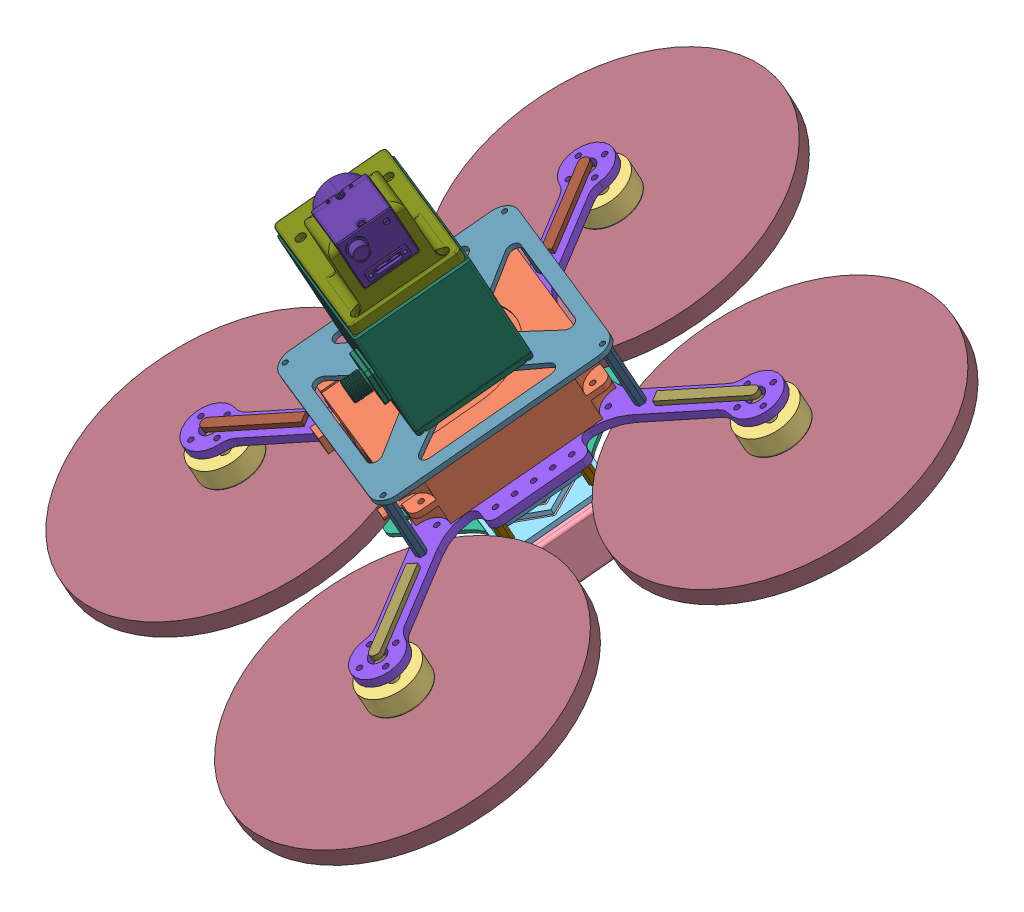
SolidWorks assembly yunque-M, configuration 默认. Lengths in mm.
Overall size (433.72 298.75 419.83).
35 component instances, 18 part files, 70 mates.
Components (placement in the parent):
- CUAV Nora飞控-1: CUAV Nora飞控 [默认] at (-183.0689 -174.3038 102.8039) x (0.916661 0.047717 0.396806) z (-0.335209 -0.448868 0.828343) size (64 22 46)
- intel_nuc-1: intel_nuc [默认] at (-190.8807 -143.3153 117.086) x (-0.335209 -0.448868 0.828343) z (-0.21764 0.892323 0.395465) size (117 105 32)
- T-motor F90电机-1: T-motor F90电机 [默认] at (-132.2317 -187.4888 236.3923) x (-0.916661 -0.047717 -0.396806) z (-0.335209 -0.448868 0.828343) size (34.07 34.7 34.07)
- 电池-1: 电池 [默认] at (-177.2712 -190.2979 96.5676) x (-0.916661 -0.047717 -0.396806) z (-0.335209 -0.448868 0.828343) size (108.03 30.1 54)
- 电池固定板-1: 电池固定板 [默认] at (-183.2633 -174.5466 103.2447) x (-0.916661 -0.047717 -0.396806) z (-0.335209 -0.448868 0.828343) size (95 3 56)
- 电池着陆板-1: 电池着陆板 [默认] at (-180.5748 -203.9008 87.5127) x (-0.916661 -0.047717 -0.396806) z (-0.335209 -0.448868 0.828343) size (125 2 125)
- 飞控垫板-1: 飞控垫板 [默认] at (-188.7043 -152.2385 113.1314) x (0.916661 0.047717 0.396806) z (-0.335209 -0.448868 0.828343) size (40 5 40)
- 主机架碳板-1: 主机架碳板 [默认] at (-189.7925 -147.7769 115.1087) x (0.916661 0.047717 0.396806) z (-0.335209 -0.448868 0.828343) size (225.99 5 225.99)
- T-motor F90电机-2: T-motor F90电机 [默认] at (-313.7213 -196.9363 157.8287) x (-0.916661 -0.047717 -0.396806) z (-0.335209 -0.448868 0.828343) size (34.07 34.7 34.07)
- T-motor F90电机-3: T-motor F90电机 [默认] at (-65.8637 -98.6175 72.3887) x (-0.335209 -0.448868 0.828343) z (0.916661 0.047717 0.396806) size (34.07 34.7 34.07)
- T-motor F90电机-4: T-motor F90电机 [默认] at (-247.3534 -108.065 -6.1749) x (-0.916661 -0.047717 -0.396806) z (-0.335209 -0.448868 0.828343) size (34.07 34.7 34.07)
- 30mm铜柱-1: 30mm铜柱 [默认] at (-153.6807 -182.7136 137.9531) x (0.973897 0.225307 0.027593) z (0.064479 -0.391147 0.918066) size (5.77 30 5.05)
- 30mm铜柱-2: 30mm铜柱 [默认] at (-138.5963 -162.5145 100.6777) x (0.973897 0.225307 0.027593) z (0.064479 -0.391147 0.918066) size (5.77 30 5.05)
- 30mm铜柱-3: 30mm铜柱 [默认] at (-212.8459 -166.3796 68.5364) x (0.973897 0.225307 0.027593) z (0.064479 -0.391147 0.918066) size (5.77 30 5.05)
- 30mm铜柱-4: 30mm铜柱 [默认] at (-227.9303 -186.5787 105.8118) x (0.973897 0.225307 0.027593) z (0.064479 -0.391147 0.918066) size (5.77 30 5.05)
- 35mm铜柱 -1: 35mm铜柱  [默认] at (-224.3142 -120.2491 46.6399) x (0.973875 0.225437 0.027287) z (0.064804 -0.391072 0.918076) size (5.77 35 5.05)
- 35mm铜柱 -2: 35mm铜柱  [默认] at (-262.8632 -171.8689 141.8994) x (0.973897 0.225307 0.027593) z (0.064479 -0.391147 0.918066) size (5.77 35 5.05)
- 35mm铜柱 -3: 35mm铜柱  [默认] at (-118.8982 -114.7616 92.2727) x (0.973897 0.225307 0.027593) z (0.064479 -0.391147 0.918066) size (5.77 35 5.05)
- 35mm铜柱 -4: 35mm铜柱  [默认] at (-157.4472 -166.3815 187.5321) x (0.973897 0.225307 0.027593) z (0.064479 -0.391147 0.918066) size (5.77 35 5.05)
- 灯板-1: 灯板 [默认] at (-315.4624 -189.7978 160.9924) x (0.885206 0.351139 -0.305143) z (-0.411149 0.283657 -0.866311) size (53 3 6)
- 灯板-B-1: 灯板-B [默认] at (-133.9728 -180.3503 239.556) x (-0.411149 0.283657 -0.866311) z (-0.885206 -0.351139 0.305143) size (53 3 6)
- 灯板-2: 灯板 [默认] at (-248.4416 -103.6033 -4.1976) x (0.411149 -0.283657 0.866311) z (-0.885206 -0.351139 0.305143) size (53 3 6)
- 灯板-B-2: 灯板-B [默认] at (-67.6048 -91.4789 75.5524) x (-0.885206 -0.351139 0.305143) z (0.411149 -0.283657 0.866311) size (53 3 6)
- full_blade-1: full_blade [默认] at (-59.3998 -125.1195 60.6434) x (0.974969 0.21764 0.045483) z (0.045483 -0.395465 0.917354) size (180 10 180)
- full_blade-2: full_blade [默认] at (-125.7678 -213.9908 224.647) x (0.974969 0.21764 0.045483) z (0.045483 -0.395465 0.917354) size (180 10 180)
- full_blade-3: full_blade [默认] at (-240.8895 -134.5669 -17.9202) x (0.974969 0.21764 0.045483) z (0.045483 -0.395465 0.917354) size (180 10 180)
- full_blade-5: full_blade [默认] at (-307.2574 -223.4383 146.0834) x (0.974969 0.21764 0.045483) z (0.045483 -0.395465 0.917354) size (180 10 180)
- flying_LIVO-1: flying_LIVO [默认] at (-159.7602 -217.8236 77.0282) x (0.916661 0.047717 0.396806) z (-0.21764 0.892323 0.395465) size (125.6 125.3 113.3)
  - fly_base-1: fly_base [默认] at (-71.8765 52.4809 124.1) size (125.6 125.3 3)
  - AVIA-1: AVIA [Default] at (-81.3765 -48.6691 111.2) x (1 0 0) z (0 -1 0) size (91.02 64.8 76.07)
    - Livox_Avia_shell_FOV.stp-1: Livox_Avia_shell_FOV.stp [Default] at origin size (1207.64 1420.81 1420.81)
      - LIVOX_AVIA.stp-1: LIVOX_AVIA.stp [Default] at origin size (91.02 64.8 76.07)
      - LIVOX_AVIA_FOV.stp-1: LIVOX_AVIA_FOV.stp [Default] at (19.97 48.3 -38.5) x (0 0 -1) z (1 0 0) size (1420.81 1420.81 1123.13) (hidden)
  - T_cam_livox-1: T_cam_livox [默认] at (-9.0765 -10.1691 198.4) x (0 1 0) z (0 0 -1) size (59.2 89 45.5)
  - FL2-020-R0-1: FL2-020-R0 [Default] at (9.3053 -10.1691 222.9) x (0 -1 0) z (-1 0 0) size (29 29 47.76)
Mates (geometry in assembly coordinates):
- 重合1: coincident anti-aligned: plane of 主机架碳板-1 through (-247.3534 -108.065 -6.1749) normal (0.21764 -0.892323 -0.395465); plane of T-motor F90电机-4 through (-242.9992 -107.8383 -4.2901) normal (-0.21764 0.892323 0.395465)
- 同心3: concentric anti-aligned: circle of 主机架碳板-1; circle of T-motor F90电机-4
- 同心4: concentric anti-aligned: circle of 主机架碳板-1; circle of T-motor F90电机-4
- 重合2: coincident anti-aligned: plane of 主机架碳板-1 through (-247.3534 -108.065 -6.1749) normal (0.21764 -0.892323 -0.395465); plane of T-motor F90电机-2 through (-309.3672 -196.7097 159.7135) normal (-0.21764 0.892323 0.395465)
- 同心5: concentric anti-aligned: circle of 主机架碳板-1; circle of T-motor F90电机-2
- 同心6: concentric anti-aligned: circle of 主机架碳板-1; circle of T-motor F90电机-2
- 重合3: coincident anti-aligned: plane of 主机架碳板-1 through (-247.3534 -108.065 -6.1749) normal (0.21764 -0.892323 -0.395465); plane of T-motor F90电机-3 through (-64.2714 -96.4853 68.4541) normal (-0.21764 0.892323 0.395465)
- 同心7: concentric anti-aligned: circle of 主机架碳板-1; circle of T-motor F90电机-3
- 同心8: concentric anti-aligned: circle of 主机架碳板-1; circle of T-motor F90电机-3
- 重合4: coincident anti-aligned: plane of T-motor F90电机-1 through (-127.8775 -187.2622 238.2771) normal (-0.21764 0.892323 0.395465); plane of 主机架碳板-1 through (-247.3534 -108.065 -6.1749) normal (0.21764 -0.892323 -0.395465)
- 同心9: concentric anti-aligned: circle of T-motor F90电机-1; circle of 主机架碳板-1
- 同心10: concentric anti-aligned: circle of T-motor F90电机-1; circle of 主机架碳板-1
- 重合9: coincident anti-aligned: plane of intel_nuc-1 through (-190.8807 -143.3153 117.086) normal (0.21764 -0.892323 -0.395465); plane of 主机架碳板-1 through (-248.4416 -103.6033 -4.1976) normal (-0.21764 0.892323 0.395465)
- 同心17: concentric aligned: circle of intel_nuc-1; circle of 主机架碳板-1
- 同心18: concentric aligned: circle of intel_nuc-1; circle of 主机架碳板-1
- 重合15: coincident anti-aligned: plane of 飞控垫板-1 through (-189.7925 -147.7769 115.1087) normal (-0.21764 0.892323 0.395465); plane of 主机架碳板-1 through (-247.3534 -108.065 -6.1749) normal (0.21764 -0.892323 -0.395465)
- 同心22: concentric anti-aligned: circle of 飞控垫板-1; circle of 主机架碳板-1
- 同心23: concentric anti-aligned: circle of 飞控垫板-1; circle of 主机架碳板-1
- 重合16: coincident anti-aligned: plane of 主机架碳板-1 through (-247.3534 -108.065 -6.1749) normal (0.21764 -0.892323 -0.395465); plane of 30mm铜柱-4 through (-234.4595 -159.809 117.6758) normal (-0.21764 0.892323 0.395465)
- 同心24: concentric aligned: circle of 主机架碳板-1; circle of 30mm铜柱-4
- 重合17: coincident anti-aligned: plane of 主机架碳板-1 through (-247.3534 -108.065 -6.1749) normal (0.21764 -0.892323 -0.395465); plane of 30mm铜柱-3 through (-219.3751 -139.6099 80.4003) normal (-0.21764 0.892323 0.395465)
- 同心25: concentric aligned: circle of 主机架碳板-1; circle of 30mm铜柱-3
- 重合18: coincident anti-aligned: plane of 主机架碳板-1 through (-247.3534 -108.065 -6.1749) normal (0.21764 -0.892323 -0.395465); plane of 30mm铜柱-1 through (-160.2099 -155.9439 149.8171) normal (-0.21764 0.892323 0.395465)
- 同心26: concentric aligned: circle of 主机架碳板-1; circle of 30mm铜柱-1
- 重合19: coincident anti-aligned: plane of 主机架碳板-1 through (-247.3534 -108.065 -6.1749) normal (0.21764 -0.892323 -0.395465); plane of 30mm铜柱-2 through (-145.1255 -135.7448 112.5416) normal (-0.21764 0.892323 0.395465)
- 同心27: concentric aligned: circle of 主机架碳板-1; circle of 30mm铜柱-2
- 重合20: coincident anti-aligned: plane of 电池固定板-1 through (-183.2633 -174.5466 103.2447) normal (-0.21764 0.892323 0.395465); plane of 30mm铜柱-2 through (-138.5963 -162.5145 100.6777) normal (0.21764 -0.892323 -0.395465)
- 同心28: concentric anti-aligned: circle of 电池固定板-1; circle of 30mm铜柱-2
- 同心29: concentric aligned: cylinder of 电池固定板-1 through (-153.0278 -185.3906 136.7667) axis (-0.21764 0.892323 0.395465) radius 1.6; circle of 30mm铜柱-1
- 重合21: coincident anti-aligned: plane of CUAV Nora飞控-1 through (-183.0689 -174.3038 102.8039) normal (0.21764 -0.892323 -0.395465); plane of 电池固定板-1 through (-183.2633 -174.5466 103.2447) normal (-0.21764 0.892323 0.395465)
- 平行1: parallel anti-aligned: line of CUAV Nora飞控-1 through (-215.5285 -185.9161 111.142) axis (0.916661 0.047717 0.396806); line of 电池固定板-1 through (-154.6077 -185.1346 142.9058) axis (-0.916661 -0.047717 -0.396806)
- 重合23: coincident anti-aligned: plane of 电池-1 through (-140.4013 -182.158 136.4217) normal (-0.21764 0.892323 0.395465); plane of 电池固定板-1 through (-182.6104 -177.2236 102.0583) normal (0.21764 -0.892323 -0.395465)
- 平行2: parallel aligned: line of 电池-1 through (-128.5689 -168.6811 107.4671) axis (-0.335209 -0.448868 0.828343); line of 电池固定板-1 through (-131.6944 -165.0819 102.6831) axis (-0.335209 -0.448868 0.828343)
- 重合25: coincident anti-aligned: plane of 电池-1 through (-133.8721 -208.9277 124.5577) normal (0.21764 -0.892323 -0.395465); plane of 电池着陆板-1 through (-180.5748 -203.9008 87.5127) normal (-0.21764 0.892323 0.395465)
- 平行3: parallel anti-aligned: line of 电池固定板-1 through (-131.6944 -165.0819 102.6831) axis (-0.335209 -0.448868 0.828343); line of 电池着陆板-1 through (-173.456 -201.4547 80.8539) axis (0.335209 0.448868 -0.828343)
- 锁定1: lock: unknown of 电池-1; unknown of 电池固定板-1
- 锁定2: lock: unknown of 电池-1; unknown of 电池着陆板-1
- 锁定3: lock: unknown of CUAV Nora飞控-1; unknown of 电池固定板-1
- 重合37: coincident anti-aligned: plane of 主机架碳板-1 through (-248.4416 -103.6033 -4.1976) normal (-0.21764 0.892323 0.395465); plane of 35mm铜柱 -3 through (-118.8982 -114.7616 92.2727) normal (0.21764 -0.892323 -0.395465)
- 同心44: concentric aligned: cylinder of 主机架碳板-1 through (-117.81 -119.2232 90.2953) axis (-0.21764 0.892323 0.395465) radius 1.6; circle of 35mm铜柱 -3
- 重合38: coincident anti-aligned: plane of 主机架碳板-1 through (-248.4416 -103.6033 -4.1976) normal (-0.21764 0.892323 0.395465); plane of 35mm铜柱 -4 through (-157.4472 -166.3815 187.5321) normal (0.21764 -0.892323 -0.395465)
- 同心45: concentric aligned: circle of 主机架碳板-1; circle of 35mm铜柱 -4
- 重合39: coincident anti-aligned: plane of 主机架碳板-1 through (-248.4416 -103.6033 -4.1976) normal (-0.21764 0.892323 0.395465); plane of 35mm铜柱 -2 through (-249.9638 -166.5432 148.207) normal (0.21764 -0.892323 -0.395465)
- 同心46: concentric aligned: circle of 主机架碳板-1; circle of 35mm铜柱 -2
- 重合40: coincident anti-aligned: plane of 主机架碳板-1 through (-248.4416 -103.6033 -4.1976) normal (-0.21764 0.892323 0.395465); plane of 35mm铜柱 -1 through (-224.3142 -120.2491 46.6399) normal (0.21764 -0.892323 -0.395465)
- 同心47: concentric aligned: circle of 主机架碳板-1; circle of 35mm铜柱 -1
- 重合68: coincident anti-aligned: plane of 主机架碳板-1 through (-248.4416 -103.6033 -4.1976) normal (-0.21764 0.892323 0.395465); plane of 灯板-B-2 through (-66.9519 -94.1558 74.3661) normal (0.21764 -0.892323 -0.395465)
- 同心67: concentric anti-aligned: circle of 主机架碳板-1; circle of 灯板-B-2
- 平行6: parallel anti-aligned: line of 主机架碳板-1 through (-117.713 -117.6421 99.4244) axis (0.885206 0.351139 -0.305143); line of 灯板-B-2 through (-66.3714 -92.3298 78.1514) axis (-0.885206 -0.351139 0.305143)
- 重合70: coincident anti-aligned: plane of 主机架碳板-1 through (-248.4416 -103.6033 -4.1976) normal (-0.21764 0.892323 0.395465); plane of 灯板-B-1 through (-133.3199 -183.0272 238.3696) normal (0.21764 -0.892323 -0.395465)
- 同心68: concentric anti-aligned: circle of 主机架碳板-1; circle of 灯板-B-1
- 平行7: parallel aligned: line of 主机架碳板-1 through (-133.4336 -175.7349 221.8527) axis (-0.411149 0.283657 -0.866311); line of 灯板-B-1 through (-131.3172 -179.2968 238.6406) axis (-0.411149 0.283657 -0.866311)
- 同心69: concentric aligned: circle of 主机架碳板-1; circle of 灯板-2
- 重合73: coincident anti-aligned: plane of 主机架碳板-1 through (-248.4416 -103.6033 -4.1976) normal (-0.21764 0.892323 0.395465); plane of 灯板-2 through (-248.4416 -103.6033 -4.1976) normal (0.21764 -0.892323 -0.395465)
- 平行8: parallel aligned: line of 主机架碳板-1 through (-248.3279 -110.8957 12.3194) axis (0.411149 -0.283657 0.866311); line of 灯板-2 through (-251.7501 -101.9798 -2.0958) axis (0.411149 -0.283657 0.866311)
- 重合75: coincident anti-aligned: plane of 主机架碳板-1 through (-248.4416 -103.6033 -4.1976) normal (-0.21764 0.892323 0.395465); plane of 灯板-1 through (-314.8095 -192.4747 159.806) normal (0.21764 -0.892323 -0.395465)
- 同心70: concentric anti-aligned: circle of 主机架碳板-1; circle of 灯板-1
- 平行9: parallel aligned: line of 主机架碳板-1 through (-297.1872 -188.835 161.2916) axis (0.885206 0.351139 -0.305143); line of 灯板-1 through (-314.229 -190.6487 163.5913) axis (0.885206 0.351139 -0.305143)
- 重合77: coincident anti-aligned: plane of T-motor F90电机-3 through (-61.5762 -116.1962 64.5981) normal (0.21764 -0.892323 -0.395465); plane of full_blade-1 through (-61.5762 -116.1962 64.5981) normal (-0.21764 0.892323 0.395465)
- 同心71: concentric anti-aligned: circle of T-motor F90电机-3; circle of full_blade-1
- 同心73: concentric anti-aligned: circle of T-motor F90电机-4; circle of full_blade-3
- 重合80: coincident anti-aligned: plane of T-motor F90电机-4 through (-243.0658 -125.6437 -13.9656) normal (0.21764 -0.892323 -0.395465); plane of full_blade-3 through (-243.0658 -125.6437 -13.9656) normal (-0.21764 0.892323 0.395465)
- 同心74: concentric anti-aligned: circle of T-motor F90电机-4; circle of full_blade-3
- 重合81: coincident anti-aligned: plane of T-motor F90电机-1 through (-127.9442 -205.0676 228.6016) normal (0.21764 -0.892323 -0.395465); plane of full_blade-2 through (-127.9442 -205.0676 228.6016) normal (-0.21764 0.892323 0.395465)
- 同心75: concentric anti-aligned: circle of T-motor F90电机-1; circle of full_blade-2
- 重合82: coincident anti-aligned: plane of T-motor F90电机-2 through (-309.4338 -214.5151 150.038) normal (0.21764 -0.892323 -0.395465); plane of full_blade-5 through (-309.4338 -214.5151 150.038) normal (-0.21764 0.892323 0.395465)
- 同心76: concentric anti-aligned: circle of T-motor F90电机-2; circle of full_blade-5
- 重合83: coincident anti-aligned: plane of 35mm铜柱 -3 through (-126.5156 -83.5303 106.1139) normal (-0.21764 0.892323 0.395465); plane of flying_LIVO-1/fly_base-1 through (-235.0636 -86.959 54.1122) normal (0.21764 -0.892323 -0.395465)
- 同心77: concentric aligned: cylinder of 35mm铜柱 -1 through (-231.9316 -89.0178 60.4812) axis (0.21764 -0.892323 -0.395465) radius 2; cylinder of flying_LIVO-1/fly_base-1 through (-232.5845 -86.3408 61.6676) axis (0.21764 -0.892323 -0.395465) radius 1.5
- 同心78: concentric aligned: cylinder of 35mm铜柱 -2 through (-270.4806 -140.6376 155.7407) axis (0.21764 -0.892323 -0.395465) radius 2; cylinder of flying_LIVO-1/fly_base-1 through (-271.1336 -137.9607 156.9271) axis (0.21764 -0.892323 -0.395465) radius 1.5
